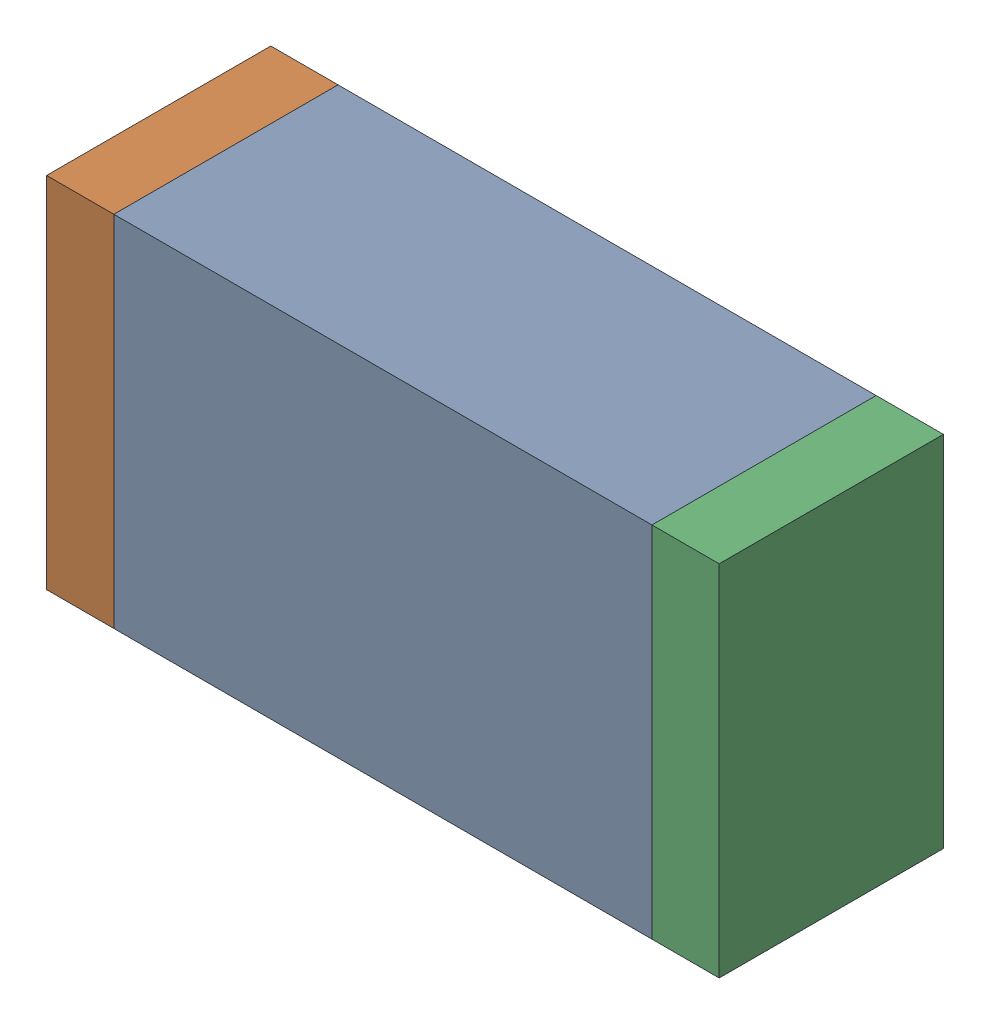
SolidWorks assembly R11, configuration Default. Lengths in mm.
Overall size (1.5 0.8 0.5).
6 component instances, 2 part files, 0 mates.
Components (placement in the parent):
- 836752368-1: 836752368 [Default] at (116 36.85 0) size (1.2 0.8 0.5)
  - Extruded-1: Extruded [Default] at origin size (1.2 0.8 0.5)
- 836752496-1: 836752496 [Default] at (115.325 36.85 0) size (0.15 0.8 0.5)
  - Extruded_2-1: Extruded_2 [Default] at origin size (0.15 0.8 0.5)
- 836752496-2: 836752496 [Default] at (116.675 36.85 0) size (0.15 0.8 0.5)
  - Extruded_2-1: Extruded_2 [Default] at origin size (0.15 0.8 0.5)
